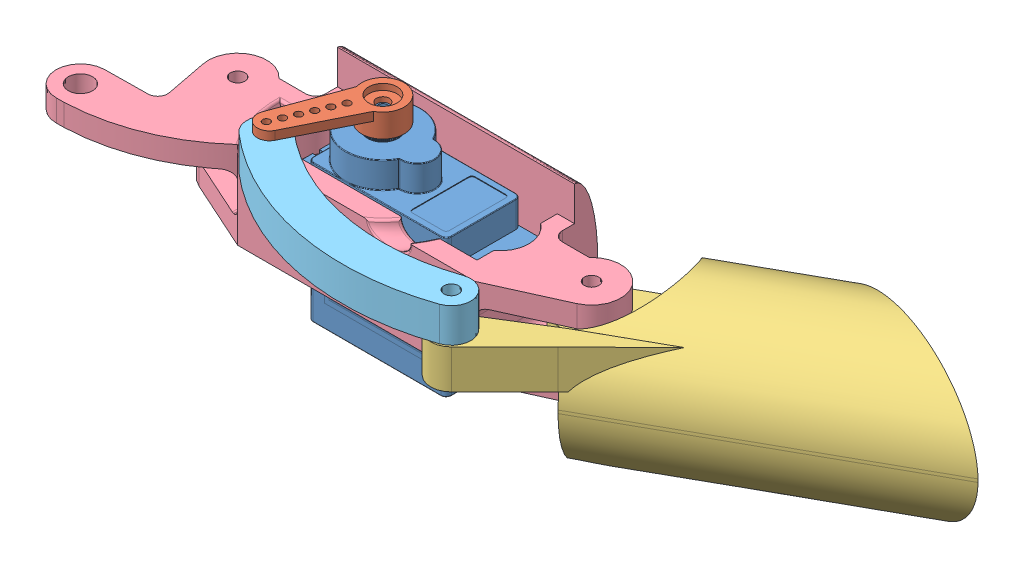
SolidWorks assembly Auriculaire, configuration Default. Lengths in mm.
Overall size (127.82 31.75 65.87).
6 component instances, 5 part files, 9 mates.
Components (placement in the parent):
- SG90 - Micro Servo Assembly-1: SG90 - Micro Servo Assembly [Default] at (4.8971 14.1291 22.7262) size (32.1 31.75 22.59) (flexible)
  - SG90 - Micro Servo 9g - Tower Pro.1-2: SG90 - Micro Servo 9g - Tower Pro.1 [Peça] at origin size (32.1 29.95 12.4)
  - SG90 - Micro Servo 9g - Tower Pro.2-2: SG90 - Micro Servo 9g - Tower Pro.2 [Peça] at (-5.15 21.1 0) x (0.395608 0 -0.91842) z (0.91842 0 0.395608) size (19.5 3.8 6.9)
- phalange2_Auriculaire-1: phalange2_Auriculaire [Défaut] at (28.0059 19.0073 30.509) x (0 -1 0) z (-0.873423 0 0.486962) size (29.59 28.89 66.57)
- SG90 - Servo Socket-1: SG90 - Servo Socket [Default] at (-14.194 26.1193 32.4496) x (1 0 0) z (0 1 0) size (78.25 28.27 25.4)
- Bras de levier-1: Bras de levier [Default] at (19.023 28.2411 7.24) x (0 1 0) z (0.325679 0 0.94548) size (5.59 39.35 25.4)
Mates (geometry in assembly coordinates):
- Parallel1: parallel anti-aligned: plane of SG90 - Micro Servo Assembly-1/SG90 - Micro Servo 9g - Tower Pro.1-2 through (-10.3029 21.7791 28.8262) normal (0 0 1); plane of SG90 - Servo Socket-1 through (-6.7169 11.8953 29.2746) normal (0 0 -1)
- Coincident3: coincident anti-aligned: plane of SG90 - Micro Servo Assembly-1/SG90 - Micro Servo 9g - Tower Pro.1-2 through (-10.3029 19.2791 27.9762) normal (0 -1 0); plane of SG90 - Servo Socket-1 through (-14.194 19.2791 32.4496) normal (0 1 0)
- Parallel2: parallel anti-aligned: plane of SG90 - Micro Servo Assembly-1/SG90 - Micro Servo 9g - Tower Pro.1-2 through (-6.3529 74.1738 17.4762) normal (-1 0 0); plane of SG90 - Servo Socket-1 through (-11.7969 19.2791 16.1778) normal (1 0 0)
- Concentric3: concentric aligned: circle of SG90 - Micro Servo Assembly-1/SG90 - Micro Servo 9g - Tower Pro.1-2; circle of SG90 - Servo Socket_V2-1
- Concentric4: concentric aligned: circle of phalange2-1; circle of SG90 - Servo Socket-1
- Distance2: distance = 0.381 mm anti-aligned: plane of phalange2-1 through (75.9304 22.1823 -6.3904) normal (0 1 0); plane of SG90 - Servo Socket-1 through (33.939 22.5633 22.9246) normal (0 -1 0)
- Coaxiale1: concentric anti-aligned: cylinder of SG90 - Micro Servo Assembly-1/SG90 - Micro Servo 9g - Tower Pro.2-2 through (-5.9694 35.2291 35.9974) axis (0 1 0) radius 0.6; cylinder of Bras de levier-1 through (-5.9694 33.8291 35.9974) axis (0 -1 0) radius 0.9922
- Coaxiale2: concentric anti-aligned: cylinder of phalange2-1 through (31.4314 4.192 43.2628) axis (0 1 0) radius 1.7859; cylinder of Bras de levier-1 through (31.4314 33.8291 43.2628) axis (0 -1 0) radius 1.1906
- Coïncidente1: coincident anti-aligned: plane of SG90 - Micro Servo Assembly-1/SG90 - Micro Servo 9g - Tower Pro.2-2 through (-0.2529 33.8291 22.7262) normal (0 -1 0); plane of Bras de levier-1 through (25.2272 33.8291 25.2514) normal (0 1 0)
